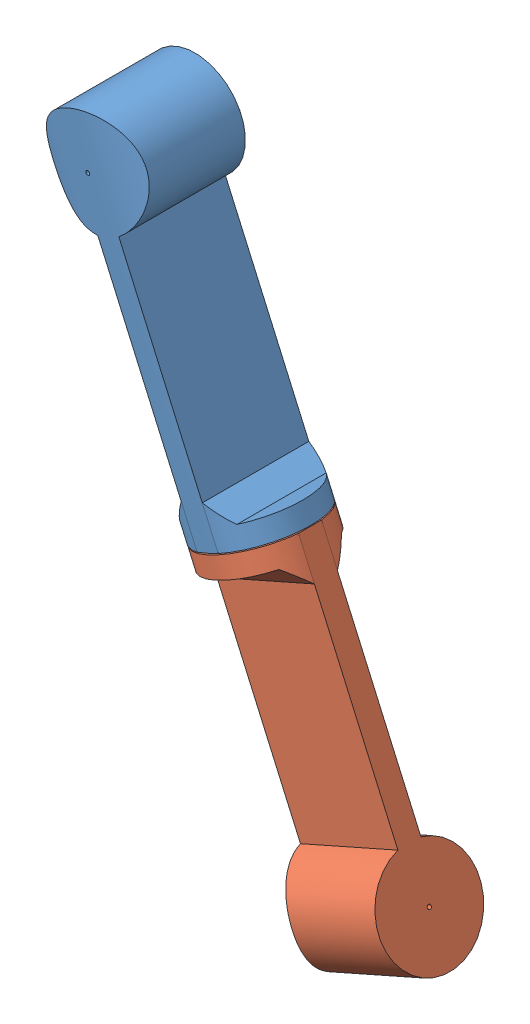
SolidWorks assembly upperarmassembly, configuration Default. Lengths in mm.
Overall size (185.69 343.24 172.56).
2 component instances, 2 part files, 3 mates.
Components (placement in the parent):
- UpperArmtop-1: UpperArmtop [Default] at (-74.0027 148.359 -6.3156) size (111.7 174.07 56.17)
- UpperArmbottom-1: UpperArmbottom [Default] at (103.7523 -271.6052 -13.6002) x (-0.163576 0.36989 -0.914562) z (-0.914562 -0.404445 0) size (111.7 174.07 56.17)
Mates (geometry in assembly coordinates):
- Concentric1: concentric: cylinder of UpperArmtop-1 through (-17.3803 -64.6797 20.7777) axis (0.404445 -0.914562 0) radius 1; cylinder of UpperArmbottom-1 through (-9.0892 -83.4282 20.7777) axis (-0.404445 0.914562 0) radius 1
- Distance1: distance = 0.5 mm: plane of UpperArmtop-1 through (-13.3359 -73.8253 -6.8156) normal (0.404445 -0.914562 0); plane of UpperArmbottom-1 through (12.1021 -63.1226 20.7777) normal (-0.404445 0.914562 0)
- Perpendicular1: perpendicular: plane of UpperArmtop-1 through (-7.9737 -71.454 -6.3156) normal (0.914562 0.404445 0); plane of UpperArmbottom-1 through (11.6448 -63.3249 14.9146) normal (0 0 -1)
